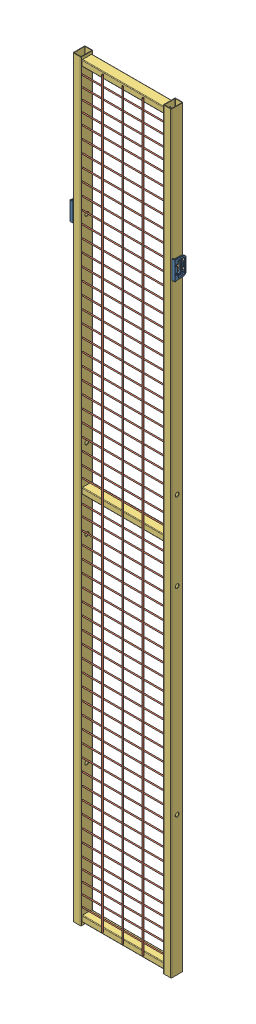
SolidWorks assembly W322-190025, configuration Default. Lengths in mm.
Overall size (265.63 1900 30).
4 component instances, 3 part files, 0 mates.
Components (placement in the parent):
- G2032-1: G2032 [Default] at (-124 600 0) size (9.31 48.01 29.42)
- G2032-2: G2032 [Default] at (124 600 0) x (-1 0 0) z (0 0 1) size (9.31 48.01 29.42)
- NÄT-50x30_II_N-05030-190-025-1: NÄT-50x30_II_N-05030-190-025 [Default] at (0 0 13.5) x (-1 0 0) z (0 0 -1) size (230 1876 4.75)
- RAM-30_RAM-190-025-1: RAM-30_RAM-190-025 [Default] at origin size (248 1900 30)
